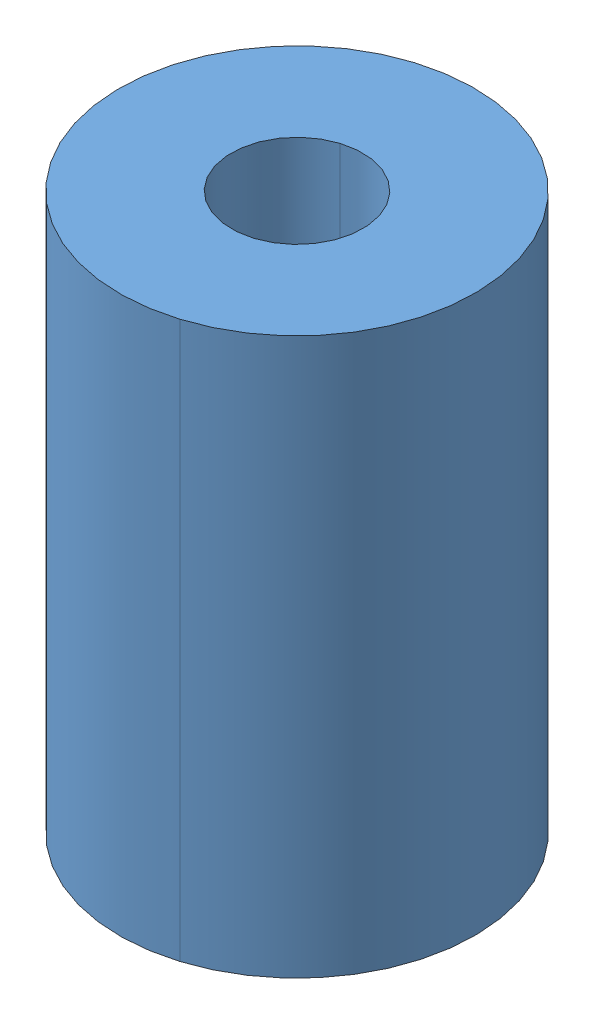
SolidWorks assembly sg90 micro servo, configuration Default. Lengths in mm.
Overall size (5.76 7.2 5.76).
2 component instances, 2 part files, 5 mates.
Components (placement in the parent):
- Part1-1: Part1 [Default] at (11.25 -26.7 0) (suppressed, hidden)
- axis.step-1: axis.step [Default] at (5.9 3.2 5.9) x (0.296886 0 0.954913) z (0 -1 0) size (4.6 4.6 7.2)
Mates (geometry in assembly coordinates):
- Concentric1: concentric anti-aligned: cylinder of Part1-1 through (5.9 0 5.9) axis (0 -1 0) radius 2.3; cylinder of axis.step-1 through (5.9 -4 5.9) axis (0 1 0) radius 2.3
- Coincident1: coincident anti-aligned: plane of Part1-1 through (22.5 -4 11.8) normal (0 1 0); plane of axis.step-1 through (5.9 -4 5.9) normal (0 -1 0)
- Coincident3: coincident anti-aligned: plane of Part1-1 through (11.25 -26.7 0) normal (0 0 -1)
- Coincident4: coincident aligned: plane of Part1-1 through (14.7 0 5.9) normal (0 1 0)
- Coincident5: coincident anti-aligned: plane of Part1-1 through (0 -26.7 11.8) normal (-1 0 0)
